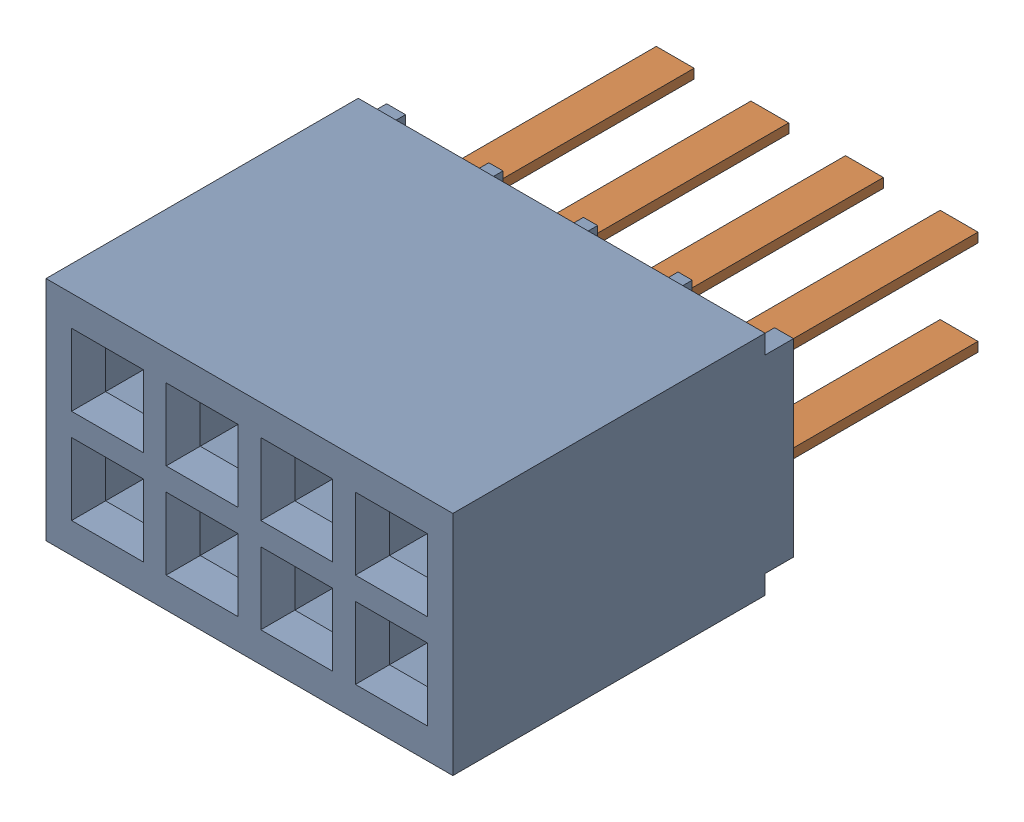
SolidWorks assembly J1, configuration ﾃﾞﾌｫﾙﾄ. Lengths in mm.
Overall size (5.46 3.05 7.62).
3 component instances, 2 part files, 0 mates.
Components (placement in the parent):
- SFMC-104-01-S-D-1: SFMC-104-01-S-D [ﾃﾞﾌｫﾙﾄ] at (68.705 40.97 0) x (-1 0 0) z (0 1 0) size (5.46 7.62 3.05)
  - _SFMC-104-01_socket-1: _SFMC-104-01_socket [ﾃﾞﾌｫﾙﾄ] at origin size (5.46 4.57 3.05)
  - _C-04-01_spins-1: _C-04-01_spins [ﾃﾞﾌｫﾙﾄ] at origin size (4.32 3.81 1.78)
